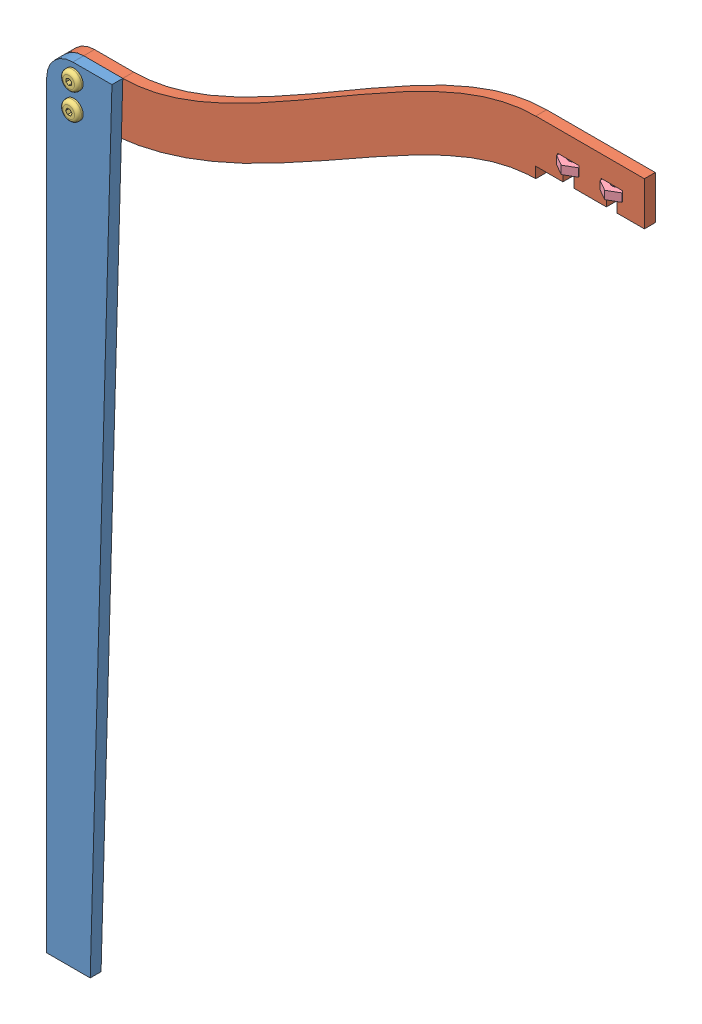
SolidWorks assembly support, configuration Default. Lengths in mm.
Overall size (171.45 304.8 10.84).
6 component instances, 4 part files, 13 mates.
Components (placement in the parent):
- support_lower-1: support_lower [Default] at (-40.5663 25.2945 4.2216) size (19.05 254 3.17)
- support_upper-1: support_upper [Default] at (91.1962 64.347 1.0466) size (171.45 66.67 3.17)
- 4-40_14_screw-1: 4-40_14_screw [Default] at (-40.5663 17.6745 1.0466) x (-0.100905 0.994896 0) z (0.994896 0.100905 0) size (5.41 7.85 5.41)
- 4-40_14_screw-2: 4-40_14_screw [Default] at (-40.5663 25.2945 1.0466) x (0.562879 0.826539 0) z (0.826539 -0.562879 0) size (5.41 7.85 5.41)
- 4-40_nut_wide-1: 4-40_nut_wide [Default] at (100.7212 71.205 2.6345) x (0.866025 0 0.5) z (-0.5 0 0.866025) size (7.33 2.38 6.35)
- 4-40_nut_wide-2: 4-40_nut_wide [Default] at (113.4212 71.205 2.6345) x (0.866025 0 0.5) z (-0.5 0 0.866025) size (7.33 2.38 6.35)
Mates (geometry in assembly coordinates):
- Concentric1: concentric aligned: cylinder of support_lower-1 through (-40.5663 25.2945 7.3966) axis (0 0 -1) radius 1.5875; cylinder of support_upper-1 through (-40.5663 25.2945 4.2216) axis (0 0 -1) radius 1.016
- Concentric2: concentric aligned: cylinder of support_lower-1 through (-40.5663 17.6745 7.3966) axis (0 0 -1) radius 1.5875; cylinder of support_upper-1 through (-40.5663 17.6745 4.2216) axis (0 0 -1) radius 1.016
- Coincident1: coincident anti-aligned: plane of support_lower-1 through (-40.8838 21.802 4.2216) normal (0 0 -1); plane of support_upper-1 through (30.9655 54.822 4.2216) normal (0 0 1)
- Concentric4: concentric aligned: cylinder of support_lower-1 through (-40.5663 25.2945 7.3966) axis (0 0 -1) radius 1.5875; cylinder of 4-40_14_screw-2 through (-40.5663 25.2945 7.3966) axis (0 0 -1) radius 1.4224
- Concentric5: concentric aligned: cylinder of support_lower-1 through (-40.5663 17.6745 7.3966) axis (0 0 -1) radius 1.5875; cylinder of 4-40_14_screw-1 through (-40.5663 17.6745 7.3966) axis (0 0 -1) radius 1.4224
- Coincident2: coincident anti-aligned: plane of support_lower-1 through (-40.8838 21.802 7.3966) normal (0 0 1); plane of 4-40_14_screw-1 through (-40.5663 17.6745 7.3966) normal (0 0 -1)
- Coincident3: coincident anti-aligned: plane of support_lower-1 through (-40.8838 21.802 7.3966) normal (0 0 1); plane of 4-40_14_screw-2 through (-40.5663 25.2945 7.3966) normal (0 0 -1)
- Coincident4: coincident anti-aligned: plane of support_upper-1 through (103.8962 73.999 4.2216) normal (-1 0 0); plane of 4-40_nut_wide-1 through (103.8962 73.5863 4.4676) normal (1 0 0)
- Coincident5: coincident anti-aligned: plane of support_upper-1 through (116.5962 73.999 4.2216) normal (-1 0 0); plane of 4-40_nut_wide-2 through (116.5962 73.5863 4.4676) normal (1 0 0)
- Coincident8: coincident anti-aligned: plane of support_upper-1 through (103.8962 71.205 4.2216) normal (0 1 0); plane of 4-40_nut_wide-1 through (103.8962 71.205 0.8015) normal (0 -1 0)
- Coincident9: coincident anti-aligned: plane of support_upper-1 through (116.5962 71.205 4.2216) normal (0 1 0); plane of 4-40_nut_wide-2 through (116.5962 71.205 0.8015) normal (0 -1 0)
- Distance1: distance = 0.2451 mm: line of support_upper-1 through (110.2462 71.205 1.0466) axis (0 1 0); line of 4-40_nut_wide-2 through (110.2462 73.5863 0.8015) axis (0 -1 0)
- Distance2: distance = 0.2451 mm: line of support_upper-1 through (97.5462 71.205 1.0466) axis (0 1 0); line of 4-40_nut_wide-1 through (97.5462 73.5863 0.8015) axis (0 -1 0)
